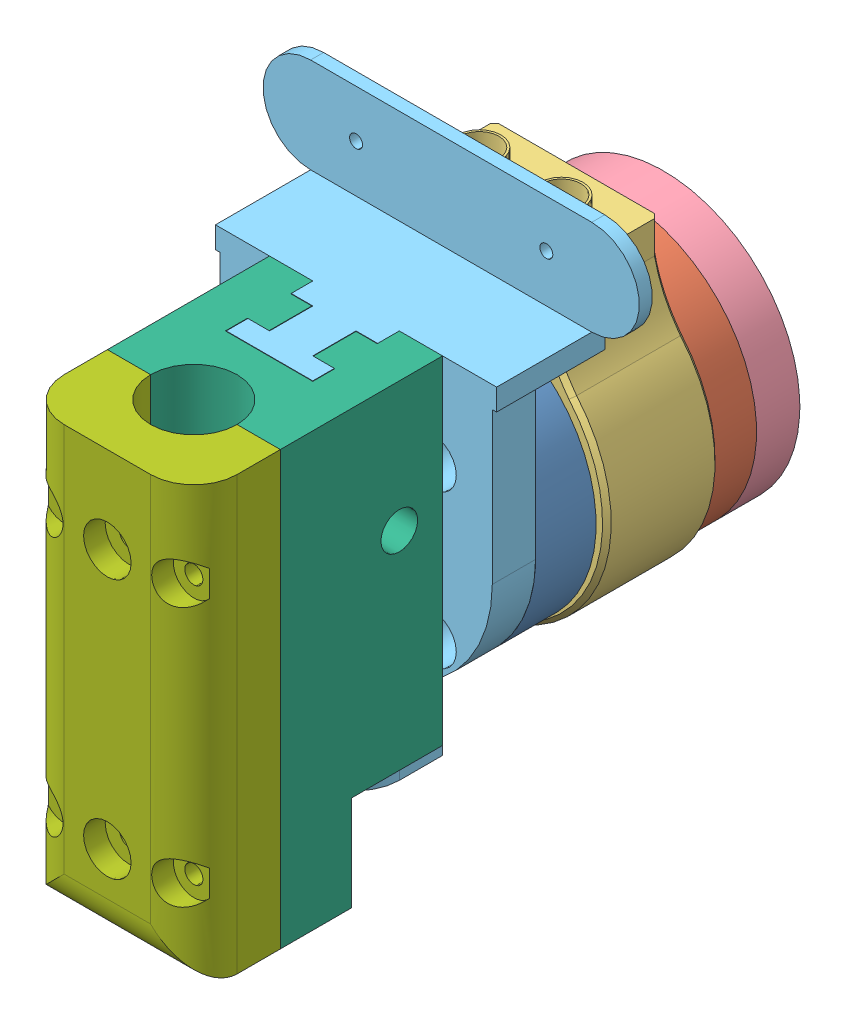
SolidWorks assembly allparttest, configuration Default. Lengths in mm.
Overall size (87 122 132.6).
7 component instances, 7 part files, 20 mates.
Components (placement in the parent):
- lastdisk-1: lastdisk [Default] at (0 0 47.1) size (63 63 15)
- middisk-1: middisk [Default] at (0 0 10) size (63 63 10)
- weisssensor-1: weisssensor [Default] at (0 0 20.1) size (66 81 27.1)
- firstdisk-1: firstdisk [Default] at origin size (63 63 14)
- cameramountv3-1: cameramountv3 [Default] at (0 0 61.1) size (87 102 45)
- markholderv1-1: markholderv1 [Default] at (0 40 71.1) size (40 100 37.5)
- lidmarkholder-1: lidmarkholder [Default] at (0 -10 108.6) size (40 100 20)
Mates (geometry in assembly coordinates):
- Coincident1: coincident aligned: plane of firstdisk-1 through (0 0 0) normal (0 0 1)
- Coincident2: coincident aligned: plane of firstdisk-1 through (0 0 0) normal (0 1 0)
- Coincident3: coincident aligned: plane of firstdisk-1 through (0 0 0) normal (1 0 0)
- Coincident4: coincident anti-aligned: plane of middisk-1 through (0 0 10) normal (0 0 -1); plane of firstdisk-1 through (0 0 10) normal (0 0 1)
- Concentric1: concentric aligned: circle of middisk-1; circle of firstdisk-1
- Concentric2: concentric anti-aligned: circle of middisk-1; circle of weisssensor-1
- Coincident6: coincident anti-aligned: plane of middisk-1 through (0 0 20) normal (0 0 1); plane of weisssensor-1 through (0 0 20) normal (0 0 -1)
- Coincident7: coincident anti-aligned: plane of lastdisk-1 through (0 0 47.1) normal (0 0 -1); plane of weisssensor-1 through (0 0 47.1) normal (0 0 1)
- Concentric3: concentric aligned: circle of lastdisk-1; circle of weisssensor-1
- Coincident8: coincident anti-aligned: plane of lastdisk-1 through (0 0 61.1) normal (0 0 1); plane of cameramountv3-1 through (0 0 61.1) normal (0 0 -1)
- Coincident9: coincident aligned: plane of cameramountv3-1 through (0 0 61.1) normal (1 0 0)
- Coincident10: coincident aligned: plane of cameramountv3-1 through (0 0 61.1) normal (0 1 0)
- Coincident11: coincident anti-aligned: plane of cameramountv3-1 through (-20 -38 91.1) normal (0 1 0); plane of markholderv1-1 through (0 -38 71.1) normal (0 -1 0)
- Coincident12: coincident aligned: plane of lastdisk-1 through (0 0 47.1) normal (1 0 0)
- Coincident13: coincident anti-aligned: plane of cameramountv3-1 through (-20 -38 91.1) normal (0 1 0); plane of markholderv1-1 through (0 -38 71.1) normal (0 -1 0)
- Coincident14: coincident aligned: plane of markholderv1-1 through (0 40 71.1) normal (1 0 0)
- Coincident15: coincident anti-aligned: plane of cameramountv3-1 through (0 0 71.1) normal (0 0 1); plane of markholderv1-1 through (0 -60 71.1) normal (0 0 -1)
- Coincident16: coincident aligned: plane of lidmarkholder-1 through (0 -10 108.6) normal (1 0 0)
- Coincident18: coincident aligned: line of markholderv1-1 through (20 -60 108.6) axis (0 1 0); line of lidmarkholder-1 through (20 -60 108.6) axis (0 1 0)
- Coincident19: coincident aligned: line of markholderv1-1 through (10 -60 108.6) axis (1 0 0); line of lidmarkholder-1 through (10 -60 108.6) axis (1 0 0)
